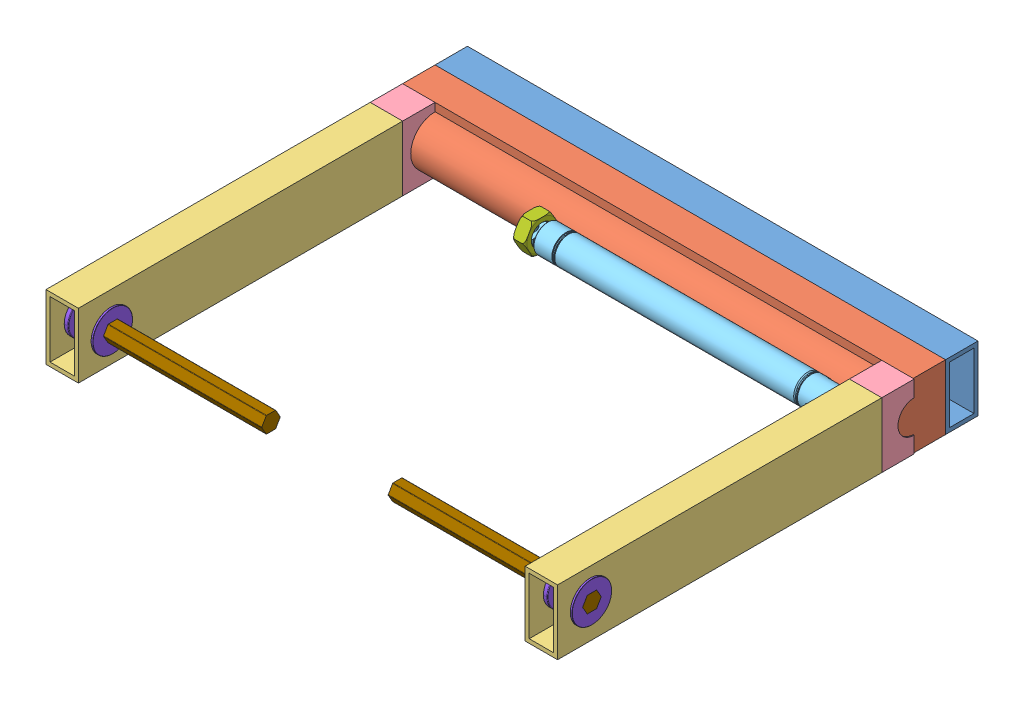
SolidWorks assembly grabber assembly, configuration Default. Lengths in mm.
Overall size (403.86 57.7 330.2).
17 component instances, 9 part files, 30 mates.
Components (placement in the parent):
- 15.7 in backplate-1: 15.7 in backplate [Default] at (-23.9848 260.3926 363.3884) size (400 50.8 25.4)
- slider-1: slider [Default] at (376.0152 311.1926 363.3884) x (-1 0 0) z (0 1 0) size (400 44.45 50.8)
- arm part-1: arm part [Default] at (1.4152 311.1926 363.3884) x (0 0 1) z (1 0 0) size (254 50.8 25.4)
- slider mechanism-1: slider mechanism [Default] at (1.4152 311.1926 388.7884) x (-1 0 0) z (0 1 0) size (25.4 25.4 50.8)
- slider mechanism-2: slider mechanism [Default] at (376.8311 311.1926 388.7884) x (-1 0 0) z (0 1 0) size (25.4 25.4 50.8)
- arm part-2: arm part [Default] at (351.4311 260.3926 363.3884) x (0 0 1) z (-1 0 0) size (254 50.8 25.4)
- cylinder.STEP-1: cylinder.STEP [Default] at (230.4001 299.2546 424.814) x (0 -0.5 0.866025) z (1 0 0) size (27.58 27.58 267.46)
  - NCME075-0600.step_NCM-Body_075E.STEP-1: NCME075-0600.step_NCM-Body_075E.STEP [Default] at origin size (21.84 21.85 254.76)
  - NCME075-0600.step_NCM-Rod_075.STEP-1: NCME075-0600.step_NCM-Rod_075.STEP [Default] at (0 0 -76.2) x (-1 0 0) z (0 0 1) size (19.05 19.05 225.13)
  - NCME075-0600.step_NCM-Nut_075.STEP-1: NCME075-0600.step_NCM-Nut_075.STEP [Default] at (0 0 128.239) x (-1 0 0) z (0 0 1) size (27.58 27.58 9.66)
  - NCME075-0600.step_NCM-Nut_075.STEP-2: NCME075-0600.step_NCM-Nut_075.STEP [Default] at (0 0 -113.919) size (27.58 27.58 9.66)
- Half inch hex flange bearing-1: Half inch hex flange bearing [Default] at (-4.9881 283.9093 642.7884) x (0 0 -1) z (1 0 0) size (31.12 31.12 7.93)
- Half inch hex flange bearing-2: Half inch hex flange bearing [Default] at (357.8344 287.6759 642.7884) x (0 0 1) z (-1 0 0) size (31.12 31.12 7.93)
- Half inch hex flange bearing-3: Half inch hex flange bearing [Default] at (370.4277 287.6759 642.7884) x (0 0 -1) z (1 0 0) size (31.12 31.12 7.93)
- Half inch hex flange bearing-4: Half inch hex flange bearing [Default] at (-17.5814 283.9093 642.7884) x (0 0 1) z (-1 0 0) size (31.12 31.12 7.93)
- half inch hex shaft 4 in long.step-1: half inch hex shaft 4 in long.step [Default] at (431.6912 283.922 642.7957) x (0 0.866025 0.5) z (-1 0 0) size (14.48 12.67 152.4)
- half inch hex shaft 4 in long.step-2: half inch hex shaft 4 in long.step [Default] at (-78.8449 287.6632 642.7957) x (0 0.866025 0.5) z (1 0 0) size (14.48 12.67 152.4)
Mates (geometry in assembly coordinates):
- Coincident1: coincident anti-aligned: plane of 15.7 in backplate-1 through (376.0152 260.3926 363.3884) normal (0 0 1); plane of slider-1 through (-23.9848 311.1926 363.3884) normal (0 0 -1)
- Coincident2: coincident aligned: plane of 15.7 in backplate-1 through (376.0152 311.1926 363.3884) normal (0 1 0); plane of slider-1 through (-23.9848 311.1926 388.7884) normal (0 1 0)
- Coincident3: coincident aligned: plane of 15.7 in backplate-1 through (376.0152 260.3926 363.3884) normal (1 0 0); plane of slider-1 through (376.0152 285.7926 388.7884) normal (1 0 0)
- Coincident4: coincident anti-aligned: plane of slider-1 through (-23.9848 304.8426 388.7884) normal (0 0 1); plane of slider mechanism-1 through (-23.9848 311.1926 388.7884) normal (0 0 -1)
- Coincident5: coincident aligned: plane of slider-1 through (-23.9848 311.1926 388.7884) normal (0 1 0); plane of slider mechanism-1 through (-23.9848 311.1926 388.7884) normal (0 1 0)
- Concentric1: concentric aligned: cylinder of slider-1 through (-23.9848 285.7926 388.7884) axis (1 0 0) radius 19.05; cylinder of slider mechanism-2 through (351.4311 285.7926 388.7884) axis (1 0 0) radius 12.7
- Coincident6: coincident aligned: plane of slider-1 through (-23.9848 311.1926 388.7884) normal (0 1 0); plane of slider mechanism-2 through (351.4311 311.1926 388.7884) normal (0 1 0)
- Coincident7: coincident aligned: plane of arm part-1 through (1.4152 311.1926 668.1884) normal (0 1 0); plane of slider mechanism-1 through (-23.9848 311.1926 388.7884) normal (0 1 0)
- Coincident8: coincident aligned: plane of arm part-1 through (-23.9848 311.1926 668.1884) normal (-1 0 0); plane of slider mechanism-1 through (-23.9848 311.1926 388.7884) normal (-1 0 0)
- Coincident10: coincident aligned: plane of slider mechanism-2 through (351.4311 311.1926 388.7884) normal (0 1 0); plane of arm part-2 through (351.4311 311.1926 668.1884) normal (0 1 0)
- Coincident11: coincident aligned: plane of slider mechanism-2 through (376.8311 311.1926 388.7884) normal (1 0 0); plane of arm part-2 through (376.8311 260.3926 668.1884) normal (1 0 0)
- Coincident13: coincident aligned: plane of slider-1 through (-23.9848 285.7926 388.7884) normal (-1 0 0); plane of slider mechanism-1 through (-23.9848 311.1926 388.7884) normal (-1 0 0)
- Coincident14: coincident aligned: plane of slider mechanism-2 through (351.4311 311.1926 388.7884) normal (0 1 0); plane of cylinder.STEP-1/NCME075-0600.step_NCM-Nut_075.STEP-1 through (363.4651 311.1926 417.9216) normal (0 1 0)
- Coincident15: coincident aligned: plane of arm part-2 through (376.8311 260.3926 668.1884) normal (1 0 0); plane of cylinder.STEP-1/NCME075-0600.step_NCM-Rod_075.STEP-1 through (376.8311 299.2546 424.814) normal (1 0 0)
- Coincident16: coincident anti-aligned: plane of arm part-1 through (1.4152 311.1926 668.1884) normal (1 0 0); plane of Half inch hex flange bearing-1 through (1.4152 283.9093 628.8184) normal (-1 0 0)
- Concentric2: concentric aligned: cylinder of arm part-1 through (1.4152 283.9093 642.7884) axis (-1 0 0) radius 12.7; cylinder of Half inch hex flange bearing-1 through (2.9392 283.9093 642.7884) axis (-1 0 0) radius 14.2875
- Coincident17: coincident anti-aligned: plane of arm part-1 through (-23.9848 311.1926 668.1884) normal (-1 0 0); plane of Half inch hex flange bearing-4 through (-23.9848 283.9093 656.7584) normal (1 0 0)
- Concentric3: concentric anti-aligned: cylinder of arm part-1 through (1.4152 283.9093 642.7884) axis (-1 0 0) radius 12.7; cylinder of Half inch hex flange bearing-4 through (-25.5088 283.9093 642.7884) axis (1 0 0) radius 14.2875
- Coincident18: coincident anti-aligned: plane of arm part-2 through (376.8311 260.3926 668.1884) normal (1 0 0); plane of Half inch hex flange bearing-3 through (376.8311 287.6759 628.8184) normal (-1 0 0)
- Concentric4: concentric anti-aligned: cylinder of arm part-2 through (351.4311 287.6759 642.7884) axis (1 0 0) radius 12.7; cylinder of Half inch hex flange bearing-3 through (378.3551 287.6759 642.7884) axis (-1 0 0) radius 14.2875
- Coincident19: coincident anti-aligned: plane of arm part-2 through (351.4311 260.3926 668.1884) normal (-1 0 0); plane of Half inch hex flange bearing-2 through (351.4311 287.6759 656.7584) normal (1 0 0)
- Concentric5: concentric aligned: cylinder of arm part-2 through (351.4311 287.6759 642.7884) axis (1 0 0) radius 12.7; cylinder of Half inch hex flange bearing-2 through (349.9071 287.6759 642.7884) axis (1 0 0) radius 14.2875
- Coincident20: coincident anti-aligned: plane of slider mechanism-2 through (351.4311 311.1926 414.1884) normal (0 0 1); plane of arm part-2 through (217.8271 311.1926 414.1884) normal (0 0 -1)
- Coincident21: coincident anti-aligned: plane of arm part-1 through (135.0192 260.3926 414.1884) normal (0 0 -1); plane of slider mechanism-1 through (-23.9848 311.1926 414.1884) normal (0 0 1)
- Coincident22: coincident aligned: plane of Half inch hex flange bearing-4 through (-25.5088 283.9093 658.3459) normal (-1 0 0); plane of half inch hex shaft 4 in long.step-1 through (-25.5088 290.2593 646.4546) normal (-1 0 0)
- Coincident23: coincident anti-aligned: plane of Half inch hex flange bearing-4 through (-25.5088 290.2593 639.1222) normal (0 -1 0); plane of half inch hex shaft 4 in long.step-1 through (-25.5088 290.2593 646.4546) normal (0 1 0)
- Coincident24: coincident anti-aligned: plane of Half inch hex flange bearing-4 through (-25.5088 290.2593 646.4546) normal (0 -0.5 -0.866025); plane of half inch hex shaft 4 in long.step-1 through (-25.5088 283.922 650.1134) normal (0 0.5 0.866025)
- Coincident25: coincident aligned: plane of Half inch hex flange bearing-3 through (378.3551 287.6759 627.2309) normal (1 0 0); plane of half inch hex shaft 4 in long.step-2 through (378.3551 294.0005 646.4546) normal (1 0 0)
- Coincident26: coincident anti-aligned: plane of Half inch hex flange bearing-3 through (378.3551 281.3259 639.1222) normal (0 1 0); plane of half inch hex shaft 4 in long.step-2 through (378.3551 281.3259 646.4546) normal (0 -1 0)
- Coincident27: coincident anti-aligned: plane of Half inch hex flange bearing-3 through (378.3551 281.3259 646.4546) normal (0 0.5 -0.866025); plane of half inch hex shaft 4 in long.step-2 through (378.3551 287.6632 650.1134) normal (0 -0.5 0.866025)
